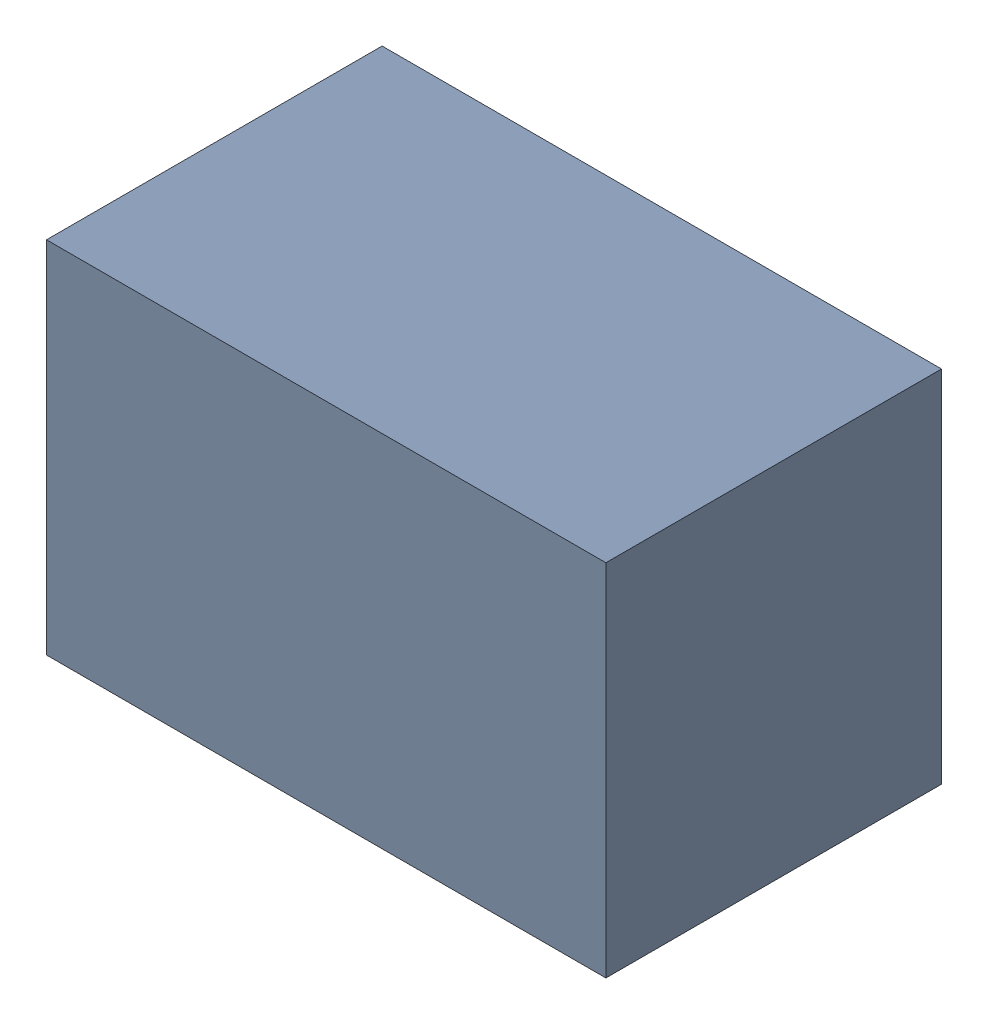
SolidWorks assembly C23, configuration Default. Lengths in mm.
Overall size (2.1 1.35 1.26).
2 component instances, 1 part files, 0 mates.
Components (placement in the parent):
- 407985824-1: 407985824 [Default] at (60.198 44.196 0.0127) size (2.1 1.35 1.26)
  - Extruded_2-1: Extruded_2 [Default] at origin size (2.1 1.35 1.26)
